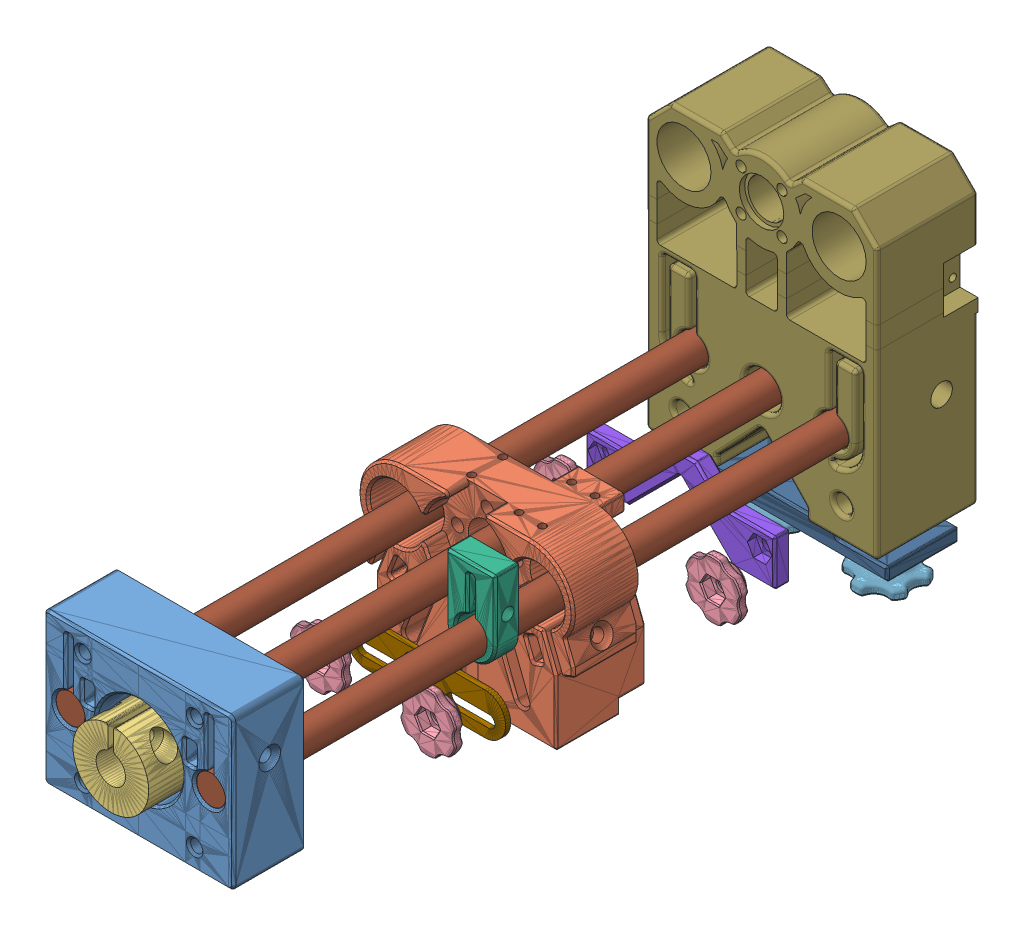
SolidWorks assembly Open source syringe pump, configuration Default. Lengths in mm.
Overall size (64.68 118.84 231.71).
18 component instances, 12 part files, 16 mates.
Components (placement in the parent):
- backSupport-1: backSupport [Default] at (-27.548 -40.2672 -51.1097) size (52.6 42 20)
- carriage-1: carriage [Default] at (-27.4353 -17.0953 -128.5929) x (1 0 0) z (0 0 -1) size (59.66 47.11 25)
- coupling-1: coupling [Default] at (-27.3942 -18.6966 -49.2269) size (21 20.88 26)
- handKnob8mm-1: handKnob8mm [Default] at (-5.7073 -37.6756 -168.3587) x (-1 0 0) z (0 0 -1) size (15.24 15.97 5.4)
- handKnob9mm-1: handKnob9mm [Default] at (-43.6672 -65.4549 -225.3866) x (1 0 0) z (0 1 0) size (16.67 18 5.4)
- limitStop-1: limitStop [Default] at (-8.4953 -17.2208 -111.0055) size (13.7 23.88 7)
- plungerHolders-1: plungerHolders [Default] at (-26.4061 -40.1982 -139.5929) size (36.84 14 4.4)
- sideSyringeHolder-1: sideSyringeHolder [Default] at (-28.8255 -40.1965 -186.7901) size (52.6 19.92 4.4)
- slider-1: slider [Default] at (-28.1685 -38.7981 -110.0767) size (44.25 11.5 4)
- topSyringeHolder25mm-1: topSyringeHolder25mm [Default] at (-27.6722 -34.5384 -232.3775) size (52.6 5.7 20)
- Part32^Open source syringe pump-2: Part32^Open source syringe pump [Default] at (-8.0609 -18.3086 -31.7097) size (8 8 200) (virtual)
- Part32^Open source syringe pump-3: Part32^Open source syringe pump [Default] at (-47.0351 -18.3086 -31.7097) x (-0.165089 0.986279 0) z (0 0 1) size (8 8 200) (virtual)
- Part32^Open source syringe pump-4: Part32^Open source syringe pump [Default] at (-27.548 -18.3086 -31.7097) size (8 8 200) (virtual)
- ToolHolderRevamped_shorter7mm-1: ToolHolderRevamped_shorter7mm [Default] at (-55.6281 -46.0757 -222.7875) x (0 -1 0) z (1 0 0) size (118.84 51.3 64.68)
- handKnob8mm-2: handKnob8mm [Default] at (-47.9044 -35.7804 -168.3587) x (-1 0 0) z (0 0 -1) size (15.24 15.97 5.4)
- handKnob8mm-3: handKnob8mm [Default] at (-12.4415 -36.6955 -96.0479) x (-1 0 0) z (0 0 -1) size (15.24 15.97 5.4)
- handKnob8mm-4: handKnob8mm [Default] at (-43.0975 -36.7315 -96.0479) x (-1 0 0) z (0 0 -1) size (15.24 15.97 5.4)
- handKnob9mm-3: handKnob9mm [Default] at (-12.9216 -65.4549 -224.0755) x (1 0 0) z (0 1 0) size (16.67 18 5.4)
Mates (geometry in assembly coordinates):
- Coincident5: coincident anti-aligned: circle of Part32^Open source syringe pump-3
- Coincident6: coincident anti-aligned: circle of Part32^Open source syringe pump-4
- Coincident7: coincident aligned: circle of Part32^Open source syringe pump-2
- Parallel2: parallel anti-aligned: plane of backSupport-1 through (-27.548 2.6578 -51.1097) normal (0 1 0); plane of carriage-1 through (-27.4353 -51.3391 -128.5929) normal (0 -1 0)
- Parallel3: parallel anti-aligned: plane of Part32^Open source syringe pump-2 through (-8.0609 -18.3086 -231.7097) normal (0 0 -1); plane of ToolHolderRevamped_shorter7mm-1 through (-27.5109 -18.9186 -203.7097) normal (0 0 1)
- Parallel4: parallel anti-aligned: plane of ToolHolderRevamped_shorter7mm-1 through (-55.6281 -43.4186 -131.9166) normal (0 -1 0)
- Concentric1: concentric anti-aligned: cylinder of Part32^Open source syringe pump-2 through (-8.0609 -18.3086 -231.7097) axis (0 0 1) radius 4; cylinder of ToolHolderRevamped_shorter7mm-1 through (-8.0609 -18.3086 -131.9166) axis (0 0 -1) radius 4.15
- Coincident10: coincident aligned: plane of Part32^Open source syringe pump-4 through (-27.548 -18.3086 -231.7097) normal (0 0 -1); plane of ToolHolderRevamped_shorter7mm-1 through (-27.5109 -18.9186 -231.7097) normal (0 0 -1)
- Parallel5: parallel anti-aligned: plane of carriage-1 through (-27.4353 -51.3391 -128.5929) normal (0 -1 0)
- Parallel6: parallel aligned: plane of carriage-1 through (-27.4353 -17.0953 -121.5929) normal (0 0 1)
- Coincident13: coincident anti-aligned: plane of carriage-1 through (-27.4353 -17.0953 -139.5929) normal (0 0 -1); plane of plungerHolders-1 through (-26.4061 -40.1982 -139.5929) normal (0 0 1)
- Parallel7: parallel aligned: plane of handKnob8mm-1 through (-5.7073 -37.6756 -168.3587) normal (0 0 1)
- Coincident15: coincident aligned: plane of handKnob8mm-3 through (-12.4415 -36.6955 -96.0479) normal (0 0 1); plane of handKnob8mm-4 through (-43.0975 -36.7315 -96.0479) normal (0 0 1)
- Coincident16: coincident aligned: plane of handKnob8mm-1 through (-5.7073 -37.6756 -168.3587) normal (0 0 1); plane of handKnob8mm-2 through (-47.9044 -35.7804 -168.3587) normal (0 0 1)
- Parallel8: parallel anti-aligned: plane of handKnob9mm-1 through (-43.6672 -65.4549 -225.3866) normal (0 -1 0)
- Coincident19: coincident aligned: plane of handKnob9mm-1 through (-43.6672 -65.4549 -225.3866) normal (0 -1 0); plane of handKnob9mm-3 through (-12.9216 -65.4549 -224.0755) normal (0 -1 0)
